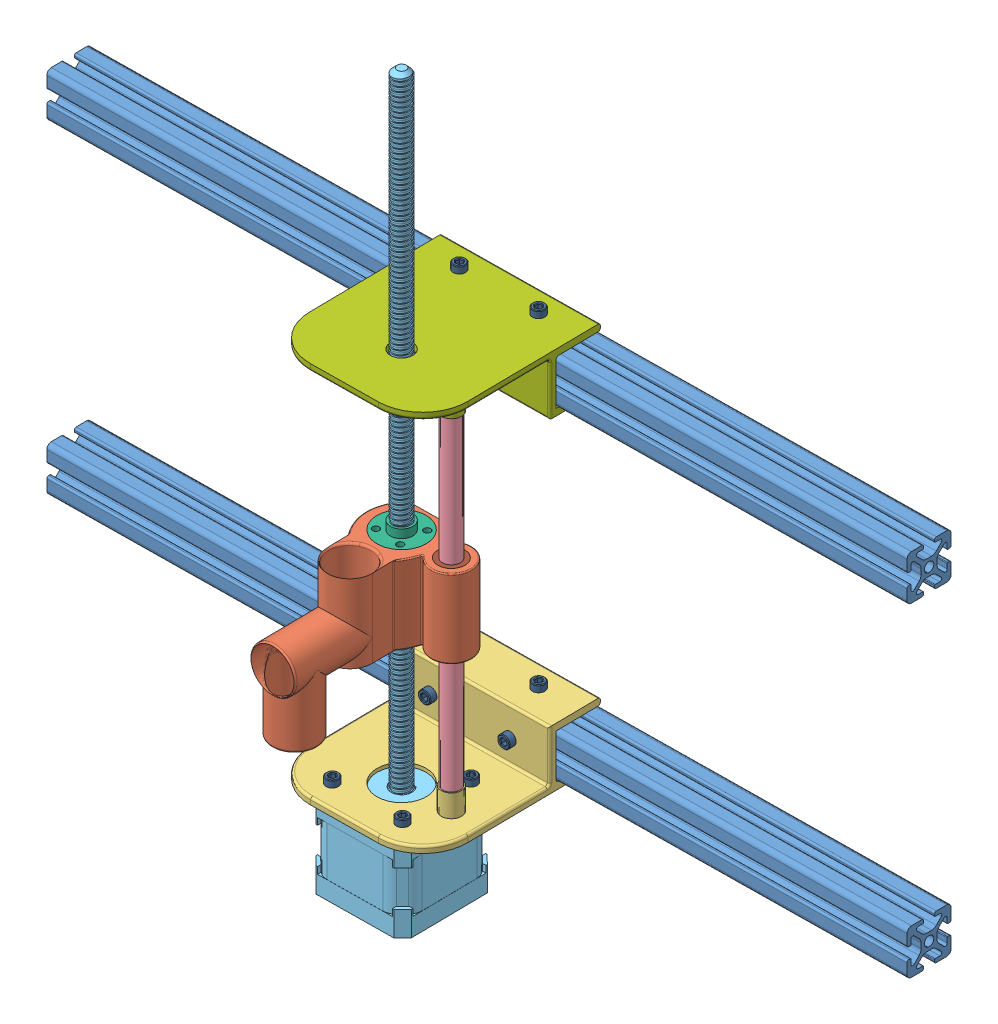
SolidWorks assembly Assem1, configuration Default. Lengths in mm.
Overall size (380.24 318.5 115.27).
28 component instances, 11 part files, 63 mates.
Components (placement in the parent):
- 8020-380.020400mm-1: 8020-380.020400mm [Default] at (225.1307 -157.9847 -98.1507) x (0.012782 0 0.999918) z (-0.999918 0 0.012782) size (19.99 19.99 380.02)
- Part3-1: Part3 [Default] at (35.86 -64.9505 -39.0817) x (-0.999918 0 0.012782) z (-0.012782 0 -0.999918) size (47.24 55.74 71)
- Part4-1: Part4 [Default] at (35.5194 -170.9796 -65.7295) x (0.012782 0 0.999918) z (-0.999918 0 0.012782) size (80 26 70)
- Part2-2: Part2 [Default] at (57.6985 -167.9796 -51.8619) x (0.999993 0 -0.003845) z (0.003845 0 0.999993) size (8 165 8)
- Pololu Stepper with 280mm LeadScrew-1: Pololu Stepper with 280mm LeadScrew [Valor predeterminado] at (35.7003 -178.9796 -51.5807) x (0.999918 0 -0.012782) z (0.012782 0 0.999918) size (42.3 318.5 42.3)
- TravelingNut-1: TravelingNut [Valor predeterminado] at (35.7003 -71.9505 -51.5807) x (0.998376 0 0.056964) z (-0.056964 0 0.998376) size (22 13.66 22)
- Part5-1: Part5 [Default] at (35.5194 0 -65.7295) x (0.012782 0 0.999918) z (0.999918 0 -0.012782) size (80 26 70)
- 8020-380.020400mm-2: 8020-380.020400mm [Default] at (225.1307 -12.9949 -98.1507) x (0 1 0) z (-0.999918 0 0.012782) size (19.99 19.99 380.02)
- 5972K910_BALL BEARING-1: 5972K910_BALL BEARING [5972K91] at (35.7003 -6.5 -51.5807) x (0.999739 0 0.022861) z (0 1 0) size (22 22 7)
- part 6-2: part 6 [Default] at (35.7003 -11 -51.5807) x (0.012782 0 0.999918) z (0.999918 0 -0.012782) size (23.55 2 25)
- M3x10-1: M3x10 [Default] at (51.3971 -164.9796 -36.2801) x (0 -1 0) z (0.006337 0 0.99998) size (13 5.5 5.5)
- M3x10-2: M3x10 [Default] at (51.0009 -164.9796 -67.2775) x (0 -1 0) z (0 0 1) size (13 5.5 5.5)
- M3x10-3: M3x10 [Default] at (20.0034 -164.9796 -66.8813) x (0 -1 0) z (0 0 1) size (13 5.5 5.5)
- M3x10-4: M3x10 [Default] at (20.3996 -164.9796 -35.8838) x (0 -1 0) z (0 0 1) size (13 5.5 5.5)
- M3x10-5: M3x10 [Default] at (17.8419 -157.9796 -79.5047) x (-0.012782 0 -0.999918) z (0.974465 -0.224194 -0.012456) size (13 5.5 5.5)
- M3x10-6: M3x10 [Default] at (52.839 -157.9796 -79.9521) x (-0.012782 0 -0.999918) z (0.974868 -0.222434 -0.012462) size (13 5.5 5.5)
- M3x10-7: M3x10 [Default] at (52.6345 -141.9796 -95.9508) x (0 -1 0) z (0 0 1) size (13 5.5 5.5)
- M3x10-8: M3x10 [Default] at (17.6374 -141.9796 -95.5034) x (0 -1 0) z (0 0 1) size (13 5.5 5.5)
- M3x10-9: M3x10 [Default] at (17.8419 -13 -79.5047) x (-0.012782 0 -0.999918) z (0.982593 0.185347 -0.01256) size (13 5.5 5.5)
- M3x10-10: M3x10 [Default] at (52.839 -13 -79.9521) x (-0.012782 0 -0.999918) z (0.982593 0.185347 -0.01256) size (13 5.5 5.5)
- M3x10-11: M3x10 [Default] at (52.6345 3 -95.9508) x (0 -1 0) z (-0.816398 0 -0.57749) size (13 5.5 5.5)
- M3x10-12: M3x10 [Default] at (17.6374 -29 -95.5034) x (0 1 0) z (0.795512 0 0.605938) size (13 5.5 5.5)
- M3x10-13: M3x10 [Default] at (17.6374 3 -95.5034) x (0 -1 0) z (0.325387 0 -0.945581) size (13 5.5 5.5)
- M3x10-15: M3x10 [Default] at (52.6345 -29 -95.9508) x (0 1 0) z (0 0 1) size (13 5.5 5.5)
- M3x10-16: M3x10 [Default] at (52.6345 -173.9796 -95.9508) x (0 1 0) z (0 0 1) size (13 5.5 5.5)
- M3x10-17: M3x10 [Default] at (17.6374 -173.9796 -95.5034) x (0 1 0) z (0 0 1) size (13 5.5 5.5)
- Part7-1: Part7 [Default] at (57.6985 -104.9505 -51.8619) x (0.99995 0 -0.00999) z (0.00999 0 0.99995) size (12 15 12)
- Part7-2: Part7 [Default] at (57.6985 -84.9505 -51.8619) x (0.999964 0 0.008501) z (-0.008501 0 0.999964) size (12 15 12)
Mates (geometry in assembly coordinates):
- Coincident18: coincident anti-aligned: plane of Part4-1 through (35.5194 -170.9796 -65.7295) normal (0 -1 0); plane of Pololu Stepper with 280mm LeadScrew-1 through (35.7003 -170.9796 -51.5807) normal (0 1 0)
- Concentric11: concentric anti-aligned: cylinder of Part4-1 through (35.7003 -177.9796 -51.5807) axis (0 1 0) radius 11.025; cylinder of Pololu Stepper with 280mm LeadScrew-1 through (35.7003 -169.4796 -51.5807) axis (0 -1 0) radius 11
- Concentric12: concentric aligned: circle of Part4-1; cylinder of Pololu Stepper with 280mm LeadScrew-1 through (20.3996 -195.9796 -35.8838) axis (0 1 0) radius 1.8537
- Concentric13: concentric anti-aligned: cone of Pololu Stepper with 280mm LeadScrew-1 through (35.7003 109.0204 -51.5807) axis (0 1 0); cylinder of TravelingNut-1 through (35.7003 -69.9505 -51.5807) axis (0 -1 0) radius 11
- Concentric14: concentric anti-aligned: cylinder of Part3-1 through (35.7003 -73.9505 -51.5807) axis (0 1 0) radius 11; cylinder of TravelingNut-1 through (35.7003 -69.9505 -51.5807) axis (0 -1 0) radius 11
- Coincident19: coincident anti-aligned: plane of Part3-1 through (35.86 -73.9505 -39.0817) normal (0 1 0); plane of TravelingNut-1 through (35.7003 -73.9505 -51.5807) normal (0 -1 0)
- Concentric16: concentric aligned: cylinder of Part4-1 through (57.6985 -157.9796 -51.8619) axis (0 -1 0) radius 4; cylinder of Part2-2 through (57.6985 -2.9796 -51.8619) axis (0 -1 0) radius 4
- Width1: width anti-aligned: plane of 8020-380.020400mm-1 through (-154.8732 -151.3596 -94.4266) normal (-0.999918 0 0.012782); plane of 8020-380.020400mm-1 through (225.1162 -151.3596 -99.284) normal (0.999918 0 -0.012782); plane of Part4-1 through (70.5165 -167.9796 -66.1769) normal (0.999918 0 -0.012782); plane of Part4-1 through (0.5222 -167.9796 -65.2822) normal (-0.999918 0 0.012782)
- Coincident23: coincident anti-aligned: plane of 8020-380.020400mm-1 through (-154.9608 -167.9796 -101.2809) normal (0 -1 0); plane of Part4-1 through (35.5194 -167.9796 -65.7295) normal (0 1 0)
- Coincident24: coincident anti-aligned: plane of 8020-380.020400mm-1 through (-154.7309 -165.973 -83.2992) normal (0.012782 0 0.999918); plane of Part4-1 through (35.2638 -144.9796 -85.7279) normal (-0.012782 0 -0.999918)
- Parallel3: parallel aligned: plane of 8020-380.020400mm-1 through (-154.7566 -147.9898 -85.3057) normal (0 1 0); plane of 8020-380.020400mm-2 through (-154.7566 -3 -85.3057) normal (0 1 0)
- Distance2: distance = 125 mm anti-aligned: plane of 8020-380.020400mm-2 through (-154.9608 -22.9898 -101.2809) normal (0 -1 0); plane of 8020-380.020400mm-1 through (-154.9608 -147.9898 -101.2809) normal (0 1 0)
- Coincident30: coincident anti-aligned: plane of Part4-1 through (35.5194 -167.9796 -65.7295) normal (0 1 0); plane of Part2-2 through (57.6985 -167.9796 -51.8619) normal (0 -1 0)
- Coincident31: coincident anti-aligned: plane of Part5-1 through (35.2638 -26 -85.7279) normal (-0.012782 0 -0.999918); plane of 8020-380.020400mm-2 through (-154.7309 -5.0066 -83.2992) normal (0.012782 0 0.999918)
- Coincident32: coincident anti-aligned: plane of Part5-1 through (35.5194 -3 -65.7295) normal (0 -1 0); plane of 8020-380.020400mm-2 through (-154.7566 -3 -85.3057) normal (0 1 0)
- Width2: width anti-aligned: plane of 8020-380.020400mm-2 through (225.046 -14.1283 -104.7752) normal (0.999918 0 -0.012782); plane of 8020-380.020400mm-2 through (-154.9434 -14.1283 -99.9179) normal (-0.999918 0 0.012782); plane of Part5-1 through (0.5222 -3 -65.2822) normal (-0.999918 0 0.012782); plane of Part5-1 through (70.5165 -3 -66.1769) normal (0.999918 0 -0.012782)
- Coincident33: coincident aligned: plane of 8020-380.020400mm-1 through (-154.7309 -149.9964 -83.2992) normal (0.012782 0 0.999918); plane of 8020-380.020400mm-2 through (-154.7309 -20.9832 -83.2992) normal (0.012782 0 0.999918)
- Coincident34: coincident aligned: plane of 8020-380.020400mm-1 through (-154.8732 -151.3596 -94.4266) normal (-0.999918 0 0.012782); plane of 8020-380.020400mm-2 through (-154.9434 -14.1283 -99.9179) normal (-0.999918 0 0.012782)
- Coincident35: coincident anti-aligned: plane of Part5-1 through (35.5194 -3 -65.7295) normal (0 -1 0); plane of 5972K910_BALL BEARING-1 through (35.9437 -3 -62.2279) normal (0 1 0)
- Concentric17: concentric anti-aligned: cylinder of Part5-1 through (35.7003 7 -51.5807) axis (0 -1 0) radius 11.0045; cylinder of 5972K910_BALL BEARING-1 through (35.7003 -3 -51.5807) axis (0 1 0) radius 11
- Coincident36: coincident anti-aligned: plane of Part5-1 through (35.5194 -11 -65.7295) normal (0 -1 0); plane of part 6-1 through (-8.605 172.2464 -24.5884) normal (-0.708357 0.570953 0.415022)
- Concentric19: concentric anti-aligned: cylinder of Part5-1 through (35.7003 -13 -51.5807) axis (0 1 0) radius 12.5; cylinder of part 6-1 through (-8.605 172.2464 -24.5884) axis (0.708357 -0.570953 -0.415022) radius 12.5
- Coincident37: coincident anti-aligned: plane of Part5-1 through (35.7003 16.9508 -51.5807) normal (0.012782 0 0.999918); plane of part 6-1 through (-8.605 172.2464 -24.5884) normal (-0.195821 0.405934 -0.892677)
- Coincident38: coincident anti-aligned: plane of Part5-1 through (35.5194 -11 -65.7295) normal (0 -1 0); plane of part 6-2 through (35.7003 -11 -51.5807) normal (0 1 0)
- Concentric20: concentric anti-aligned: cylinder of Part5-1 through (35.7003 -11 -51.5807) axis (0 -1 0) radius 11.75; cylinder of part 6-2 through (35.7003 -13 -51.5807) axis (0 1 0) radius 11.75
- Coincident40: coincident aligned: plane of Part5-1 through (35.5194 0 -65.7295) normal (0 1 0)
- Concentric21: concentric aligned: cylinder of Part4-1 through (51.3971 -177.9796 -36.2801) axis (0 1 0) radius 1.5; cylinder of M3x10-1 through (51.3971 -76.2741 -36.2801) axis (0 1 0) radius 2.75
- Coincident43: coincident anti-aligned: plane of Part4-1 through (35.5194 -167.9796 -65.7295) normal (0 1 0); plane of M3x10-4 through (21.8896 -167.9796 -35.8838) normal (0 -1 0)
- Concentric22: concentric aligned: cylinder of Part4-1 through (20.3996 -177.9796 -35.8838) axis (0 1 0) radius 1.5; cylinder of M3x10-4 through (20.3996 -76.2741 -35.8838) axis (0 1 0) radius 2.75
- Coincident44: coincident anti-aligned: plane of Part4-1 through (35.5194 -167.9796 -65.7295) normal (0 1 0); plane of M3x10-1 through (52.8871 -167.9796 -36.2895) normal (0 -1 0)
- Coincident45: coincident anti-aligned: plane of Part4-1 through (35.5194 -167.9796 -65.7295) normal (0 1 0); plane of M3x10-3 through (21.4934 -167.9796 -66.8813) normal (0 -1 0)
- Concentric23: concentric aligned: cylinder of Part4-1 through (20.0034 -177.9796 -66.8813) axis (0 1 0) radius 1.5; cylinder of M3x10-3 through (20.0034 -76.2741 -66.8813) axis (0 1 0) radius 2.75
- Coincident46: coincident anti-aligned: plane of Part4-1 through (35.5194 -167.9796 -65.7295) normal (0 1 0); plane of M3x10-2 through (52.4909 -167.9796 -67.2775) normal (0 -1 0)
- Concentric24: concentric aligned: cylinder of Part4-1 through (51.0009 -177.9796 -67.2775) axis (0 1 0) radius 1.5; cylinder of M3x10-2 through (51.0009 -76.2741 -67.2775) axis (0 1 0) radius 2.75
- Coincident48: coincident anti-aligned: plane of Part4-1 through (35.3021 -144.9796 -82.7281) normal (0.012782 0 0.999918); plane of M3x10-5 through (18.1375 -156.5275 -82.5087) normal (-0.012782 0 -0.999918)
- Concentric25: concentric aligned: cylinder of Part4-1 through (17.5862 -157.9796 -99.5031) axis (0.012782 0 0.999918) radius 1.5; cylinder of M3x10-5 through (18.9757 -157.9796 9.1935) axis (0.012782 0 0.999918) radius 2.75
- Coincident50: coincident anti-aligned: plane of Part4-1 through (35.3021 -144.9796 -82.7281) normal (0.012782 0 0.999918); plane of M3x10-6 through (53.1321 -156.5269 -82.9561) normal (-0.012782 0 -0.999918)
- Concentric26: concentric aligned: cylinder of Part4-1 through (52.5834 -157.9796 -99.9504) axis (0.012782 0 0.999918) radius 1.5; cylinder of M3x10-6 through (53.9728 -157.9796 8.7462) axis (0.012782 0 0.999918) radius 2.75
- Coincident51: coincident anti-aligned: plane of Part4-1 through (35.5194 -144.9796 -65.7295) normal (0 1 0); plane of M3x10-8 through (19.1274 -144.9796 -95.5034) normal (0 -1 0)
- Concentric27: concentric aligned: cylinder of Part4-1 through (17.6374 -147.9796 -95.5034) axis (0 1 0) radius 1.5; cylinder of M3x10-8 through (17.6374 -53.2741 -95.5034) axis (0 1 0) radius 2.75
- Coincident52: coincident anti-aligned: plane of Part4-1 through (35.5194 -144.9796 -65.7295) normal (0 1 0); plane of M3x10-7 through (54.1245 -144.9796 -95.9508) normal (0 -1 0)
- Concentric28: concentric aligned: cylinder of Part4-1 through (52.6345 -147.9796 -95.9508) axis (0 1 0) radius 1.5; cylinder of M3x10-7 through (52.6345 -53.2741 -95.9508) axis (0 1 0) radius 2.75
- Coincident54: coincident anti-aligned: plane of Part5-1 through (35.3021 -26 -82.7281) normal (0.012782 0 0.999918); plane of M3x10-9 through (17.5274 -11.5358 -82.5009) normal (-0.012782 0 -0.999918)
- Concentric30: concentric aligned: cylinder of Part5-1 through (17.5862 -13 -99.5031) axis (0.012782 0 0.999918) radius 1.5; cylinder of M3x10-9 through (18.9757 -13 9.1935) axis (0.012782 0 0.999918) radius 2.75
- Coincident55: coincident anti-aligned: plane of Part5-1 through (35.3021 -26 -82.7281) normal (0.012782 0 0.999918); plane of M3x10-10 through (52.5245 -11.5358 -82.9483) normal (-0.012782 0 -0.999918)
- Concentric31: concentric aligned: cylinder of Part5-1 through (52.5834 -13 -99.9504) axis (0.012782 0 0.999918) radius 1.5; cylinder of M3x10-10 through (53.9728 -13 8.7462) axis (0.012782 0 0.999918) radius 2.75
- Coincident57: coincident anti-aligned: plane of Part5-1 through (35.5194 0 -65.7295) normal (0 1 0); plane of M3x10-13 through (16.2284 0 -95.9882) normal (0 -1 0)
- Concentric33: concentric aligned: cylinder of Part5-1 through (17.6374 -3 -95.5034) axis (0 1 0) radius 1.5; cylinder of M3x10-13 through (17.6374 91.7055 -95.5034) axis (0 1 0) radius 2.75
- Coincident58: coincident anti-aligned: plane of Part5-1 through (35.5194 0 -65.7295) normal (0 1 0); plane of M3x10-11 through (51.774 0 -94.7343) normal (0 -1 0)
- Concentric34: concentric aligned: cylinder of Part5-1 through (52.6345 -3 -95.9508) axis (0 1 0) radius 1.5; cylinder of M3x10-11 through (52.6345 91.7055 -95.9508) axis (0 1 0) radius 2.75
- Coincident59: coincident anti-aligned: plane of Part5-1 through (35.5194 -26 -65.7295) normal (0 -1 0); plane of M3x10-12 through (16.7345 -26 -94.3181) normal (0 1 0)
- Concentric35: concentric aligned: cylinder of Part5-1 through (17.6374 -23 -95.5034) axis (0 -1 0) radius 1.5; cylinder of M3x10-12 through (17.6374 -117.7055 -95.5034) axis (0 -1 0) radius 2.75
- Coincident60: coincident anti-aligned: plane of Part5-1 through (35.5194 -26 -65.7295) normal (0 -1 0); plane of M3x10-15 through (51.1445 -26 -95.9508) normal (0 1 0)
- Concentric36: concentric aligned: circle of Part5-1; cylinder of M3x10-15 through (52.6345 -117.7055 -95.9508) axis (0 -1 0) radius 2.75
- Coincident61: coincident anti-aligned: plane of Part4-1 through (35.5194 -170.9796 -65.7295) normal (0 -1 0); plane of M3x10-16 through (51.1445 -170.9796 -95.9508) normal (0 1 0)
- Concentric37: concentric aligned: cylinder of Part4-1 through (52.6345 -167.9796 -95.9508) axis (0 -1 0) radius 1.5; cylinder of M3x10-16 through (52.6345 -262.6851 -95.9508) axis (0 -1 0) radius 2.75
- Coincident62: coincident anti-aligned: plane of Part4-1 through (35.5194 -170.9796 -65.7295) normal (0 -1 0); plane of M3x10-17 through (16.1474 -170.9796 -95.5034) normal (0 1 0)
- Concentric38: concentric aligned: cylinder of Part4-1 through (17.6374 -167.9796 -95.5034) axis (0 -1 0) radius 1.5; cylinder of M3x10-17 through (17.6374 -262.6851 -95.5034) axis (0 -1 0) radius 2.75
- Concentric39: concentric anti-aligned: cylinder of Part3-1 through (57.6985 -84.9505 -51.8619) axis (0 1 0) radius 6; cylinder of Part7-2 through (57.6985 -69.9505 -51.8619) axis (0 -1 0) radius 6
- Coincident63: coincident anti-aligned: plane of Part3-1 through (35.86 -84.9505 -39.0817) normal (0 1 0); plane of Part7-2 through (57.6985 -84.9505 -51.8619) normal (0 -1 0)
- Concentric41: concentric aligned: cylinder of Part3-1 through (57.6985 -89.9505 -51.8619) axis (0 -1 0) radius 6; cylinder of Part7-1 through (57.6985 -89.9505 -51.8619) axis (0 -1 0) radius 6
- Coincident65: coincident anti-aligned: plane of Part3-1 through (35.86 -89.9505 -39.0817) normal (0 -1 0); plane of Part7-1 through (57.6985 -89.9505 -51.8619) normal (0 1 0)
- Concentric42: concentric aligned: cylinder of Part2-2 through (57.6985 -2.9796 -51.8619) axis (0 -1 0) radius 4; cylinder of Part7-2 through (57.6985 -69.9505 -51.8619) axis (0 -1 0) radius 4
